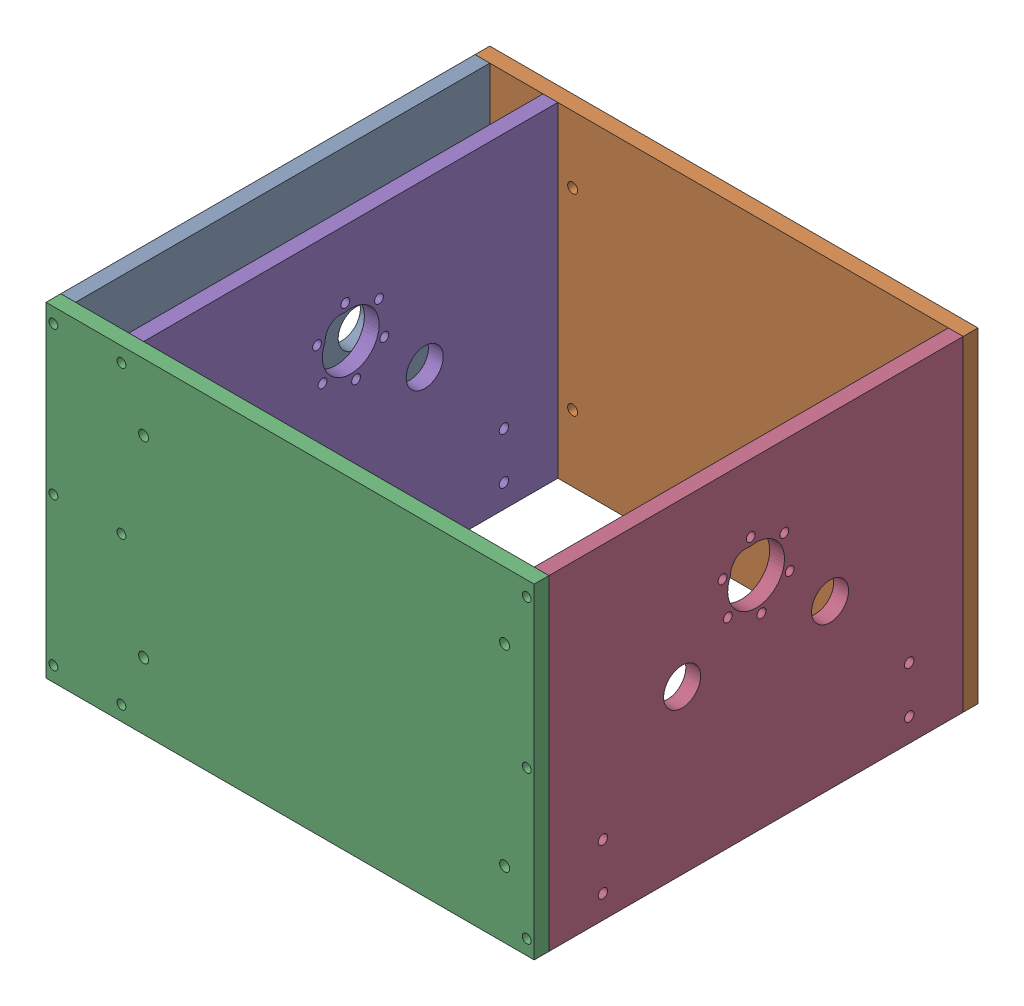
SolidWorks assembly Shredder Box, configuration Default. Lengths in mm.
Overall size (209.55 139.7 190.5).
5 component instances, 2 part files, 14 mates.
Components (placement in the parent):
- Face_Plate-1: Face_Plate [front_metal] at (-137.588 -25.7721 90.0789) x (0 0 1) z (-1 0 0) size (177.8 139.7 6.35)
- Side_Plate1-1: Side_Plate1 [Metal] at (-39.163 -25.7721 -1.9961) size (209.55 139.7 6.35)
- Side_Plate1-2: Side_Plate1 [Metal] at (-39.163 -25.7721 182.1539) size (209.55 139.7 6.35)
- Face_Plate-2: Face_Plate [front_metal] at (65.612 -25.7721 90.0789) x (0 0 1) z (-1 0 0) size (177.8 139.7 6.35)
- Face_Plate-4: Face_Plate [front_metal] at (-108.378 -25.7721 90.0789) x (0 0 1) z (-1 0 0) size (177.8 139.7 6.35)
Mates (geometry in assembly coordinates):
- Coincident3: coincident anti-aligned: plane of Side_Plate1-1 through (-91.2839 -25.7721 1.1789) normal (0 0 1); plane of Face_Plate-2 through (7.1411 -95.6221 1.1789) normal (0 0 -1)
- Coincident4: coincident anti-aligned: line of Side_Plate1-1 through (13.4911 -95.6221 1.1789) axis (0 1 0); line of Face_Plate-2 through (13.4911 44.0779 1.1789) axis (0 -1 0)
- Coincident5: coincident aligned: line of Side_Plate1-1 through (-196.0589 -95.6221 1.1789) axis (1 0 0); line of Face_Plate-2 through (7.1411 -95.6221 1.1789) axis (1 0 0)
- Coincident6: coincident anti-aligned: plane of Side_Plate1-2 through (-91.2839 -25.7721 178.9789) normal (0 0 -1); plane of Face_Plate-2 through (7.1411 -95.6221 178.9789) normal (0 0 1)
- Coincident7: coincident aligned: line of Side_Plate1-2 through (-196.0589 -95.6221 178.9789) axis (1 0 0); line of Face_Plate-2 through (7.1411 -95.6221 178.9789) axis (1 0 0)
- Coincident8: coincident aligned: line of Side_Plate1-2 through (13.4911 -95.6221 178.9789) axis (0 1 0); line of Face_Plate-2 through (13.4911 -95.6221 178.9789) axis (0 1 0)
- Coincident9: coincident anti-aligned: plane of Face_Plate-1 through (-196.0589 -95.6221 1.1789) normal (0 0 -1); plane of Side_Plate1-1 through (-91.2839 -25.7721 1.1789) normal (0 0 1)
- Coincident10: coincident anti-aligned: plane of Face_Plate-1 through (-196.0589 -95.6221 178.9789) normal (0 0 1); plane of Side_Plate1-2 through (-91.2839 -25.7721 178.9789) normal (0 0 -1)
- Coincident11: coincident anti-aligned: line of Face_Plate-1 through (-196.0589 44.0779 178.9789) axis (1 0 0); line of Side_Plate1-2 through (13.4911 44.0779 178.9789) axis (-1 0 0)
- Coincident12: coincident anti-aligned: line of Face_Plate-1 through (-196.0589 -95.6221 178.9789) axis (0 1 0); line of Side_Plate1-2 through (-196.0589 44.0779 178.9789) axis (0 -1 0)
- Coincident13: coincident anti-aligned: plane of Side_Plate1-1 through (-91.2839 -25.7721 1.1789) normal (0 0 1); plane of Face_Plate-4 through (-114.728 -95.6221 1.1789) normal (0 0 -1)
- Coincident14: coincident anti-aligned: plane of Side_Plate1-2 through (-91.2839 -25.7721 178.9789) normal (0 0 -1); plane of Face_Plate-4 through (-114.728 -95.6221 178.9789) normal (0 0 1)
- Coincident15: coincident anti-aligned: line of Side_Plate1-1 through (13.4911 44.0779 1.1789) axis (-1 0 0); line of Face_Plate-4 through (-114.728 44.0779 1.1789) axis (1 0 0)
- Distance1: distance = 22.86 mm: line of Face_Plate-1 through (-137.588 44.0779 178.9789) axis (0 0 -1); line of Face_Plate-4 through (-114.728 44.0779 178.9789) axis (0 0 -1)
